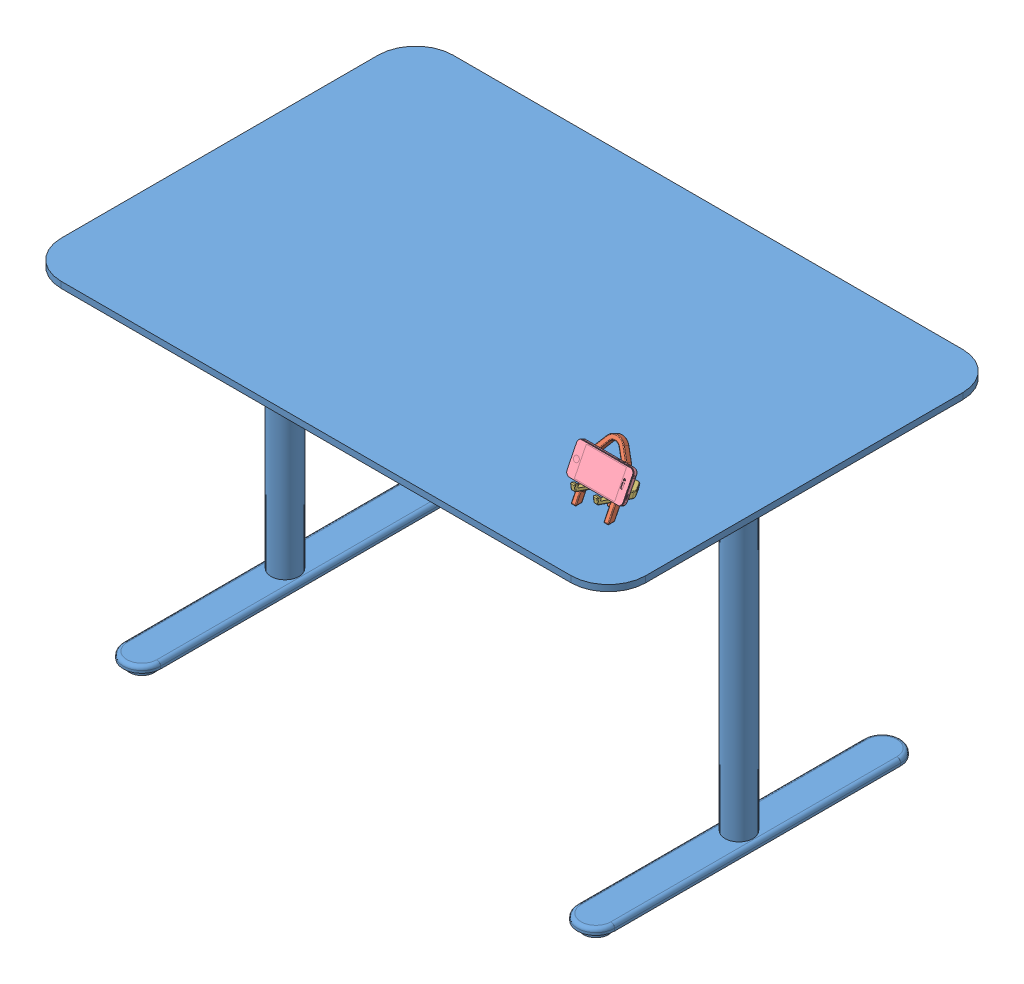
SolidWorks assembly Assem1, configuration Default. Lengths in mm.
Overall size (1193.8 818.44 800.1).
4 component instances, 4 part files, 9 mates.
Components (placement in the parent):
- Table-1: Table [Default] at origin size (1193.8 704.85 800.1)
- Outer-1: Outer [Default] at (431.8 -5.6796 262.7936) x (1 0 0) z (0 0.447214 0.894427) size (76.2 126.06 12.7)
- Inner-1: Inner [Default] at (431.8 37.6708 289.5204) x (1 0 0) z (0 0.945238 -0.326382) size (76.2 115.75 12.7)
- iPhone 12-1: iPhone 12 [Default<As Machined>] at (431.8 62.2248 248.3082) x (0 -0.894427 0.447214) z (0 0.447214 0.894427) size (60.83 116.46 9.42)
Mates (geometry in assembly coordinates):
- Concentric1: concentric aligned: cylinder of Outer-1 through (393.7 31.2379 251.4343) axis (1 0 0) radius 3.175; cylinder of Inner-1 through (-22.8903 28.068 400.3121) axis (1 0 0) radius 2.921
- Width1: width aligned: plane of Outer-1 through (403.225 64.8811 227.5132) normal (1 0 0); plane of Inner-1 through (460.375 -5.6796 262.7936) normal (-1 0 0); plane of Outer-1 through (-3.2053 45.0272 435.0153) normal (1 0 0); plane of Inner-1 through (33.6247 45.0272 435.0153) normal (-1 0 0)
- Coincident1: coincident anti-aligned: plane of Table-1 through (-520.7 0 323.85) normal (0 1 0); plane of Outer-1 through (393.7 0 274.1528) normal (0 -1 0)
- Distance3: distance = 127 mm aligned: plane of Outer-1 through (469.9 79.5146 234.3955) normal (1 0 0); plane of Table-1 through (596.9 -12.7 -323.85) normal (1 0 0)
- Distance4: distance = 127 mm: line of Outer-1 through (461.899 2.2056 273.05) axis (1 0 0); plane of Table-1 through (-520.7 -12.7 400.05) normal (0 0 1)
- Coincident2: coincident anti-aligned: plane of Outer-1 through (431.8 93.9609 227.1723) normal (0 0.447214 0.894427); plane of iPhone 12-1 through (382.524 79.0013 234.6521) normal (0 -0.447214 -0.894427)
- Width2: width aligned: plane of iPhone 12-1 through (489.7755 82.4999 241.6494) normal (1 0 0); plane of Outer-1 through (373.8245 44.1057 260.8465) normal (-1 0 0); plane of iPhone 12-1 through (469.9 79.5146 234.3955) normal (1 0 0); plane of Outer-1 through (393.7 79.5146 234.3955) normal (-1 0 0)
- Coincident4: coincident: plane of Inner-1 through (-22.8903 36.4042 428.3073) normal (0 0.958412 -0.285389); line of iPhone 12-1 through (382.524 33.5416 259.171) axis (1 0 0)
- Tangent1: tangent anti-aligned: plane of Table-1 through (-520.7 0 323.85) normal (0 1 0); torus of Inner-1
